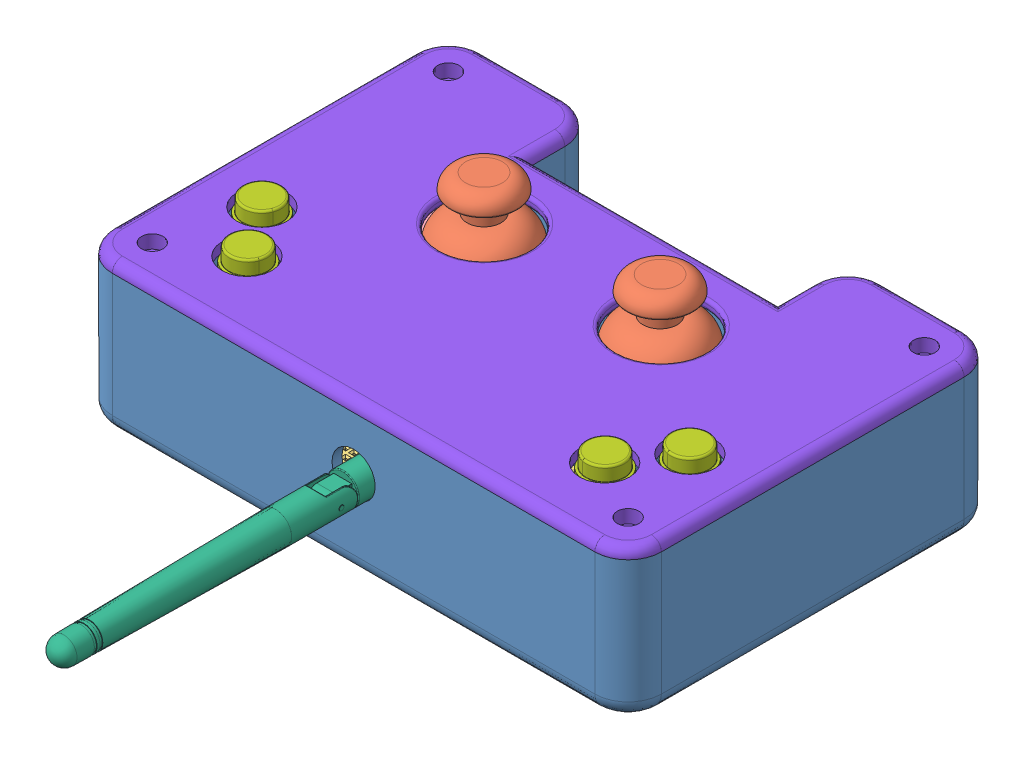
SolidWorks assembly JoystickAssembly, configuration Default. Lengths in mm.
Overall size (165 58.2 202.37).
14 component instances, 9 part files, 19 mates.
Components (placement in the parent):
- Joystick-1: Joystick [Default] at (54.0415 59.8294 130.8228) size (165 42 111)
- joy_stick_2a.step-1: joy_stick_2a.step [Default] at (94.3915 85.8294 137.6174) x (0 0 -1) z (1 0 0) size (39.77 33.6 27.6)
- joy_stick_2a.step-2: joy_stick_2a.step [Default] at (41.3913 85.8294 137.5289) x (0 0 -1) z (1 0 0) size (39.77 33.6 27.6)
- HalfBreadboard.step-1: HalfBreadboard.step [Default] at (54.0619 68.0794 113.7306) x (0 0 -1) z (1 0 0) size (56.08 9.51 83.01)
- 9V-2-1: 9V-2 [Default] at (0.3463 75.3294 87.429) x (0 1 0) z (1 0 0) size (25 49.55 16)
- NRFL24L01_Power_Board_asm-1: NRFL24L01_Power_Board_asm [Default] at (53.8164 64.2894 122.1319) size (18.6 11.5 26)
- NRF24L01L+Antenna-2: NRF24L01L+Antenna [Default] at (54.5514 76.8294 126.2969) x (0 0 1) z (-1 0 0) size (151.4 20.74 15.5)
- Button microswitch_P-B1729+B17172_blue.stp-1: Button microswitch_P-B1729+B17172_blue.stp [Default] at (118.326 95.9294 149.578) x (-0.642788 0 0.766044) z (0 1 0) size (13 13 15.4)
- Perf.stp-1: Perf.stp [Default] at (117.4296 95.9294 172.2077) x (0.642788 0 -0.766044) z (0 -1 0) size (70 50 1.55) (hidden)
- Perf.stp-2: Perf.stp [Default] at (2.032 95.9294 165.3557) x (-0.642788 0 -0.766044) z (0 -1 0) size (70 50 1.55) (hidden)
- Button microswitch_P-B1729+B17172_blue.stp-3: Button microswitch_P-B1729+B17172_blue.stp [Default] at (107.6768 95.9294 164.3561) x (-0.642788 0 0.766044) z (0 1 0) size (13 13 15.4)
- Joystick_Lid-1: Joystick_Lid [Default] at (54.0415 101.8294 130.8228) size (165 6.9 111)
- Button microswitch_P-B1729+B17172_blue.stp-4: Button microswitch_P-B1729+B17172_blue.stp [Default] at (0.4062 95.9294 164.3561) x (0.642788 0 0.766044) z (0 1 0) size (13 13 15.4)
- Button microswitch_P-B1729+B17172_blue.stp-5: Button microswitch_P-B1729+B17172_blue.stp [Default] at (-10.243 95.9294 149.578) x (0.642788 0 0.766044) z (0 1 0) size (13 13 15.4)
Mates (geometry in assembly coordinates):
- Coincident2: coincident anti-aligned: plane of Joystick-1 through (71.3417 85.8294 132.5789) normal (0 1 0); plane of joy_stick_2a.step-1 through (81.2915 85.8294 120.4674) normal (0 -1 0)
- Concentric4: concentric anti-aligned: circle of joy_stick_2a.step-1; circle of Joystick-1
- Concentric8: concentric anti-aligned: circle of Joystick-1; circle of joy_stick_2a.step-2
- Coincident4: coincident anti-aligned: plane of Joystick-1 through (38.5413 85.8294 132.5789) normal (0 1 0); plane of joy_stick_2a.step-2 through (28.2913 85.8294 120.3789) normal (0 -1 0)
- Coincident5: coincident anti-aligned: plane of Joystick-1 through (6.5415 62.8294 85.3228) normal (0 1 0); plane of HalfBreadboard.step-1 through (12.1519 62.8294 155.6406) normal (0 -1 0)
- Coincident6: coincident anti-aligned: plane of NRFL24L01_Power_Board_asm-1 through (48.7364 74.3294 132.1319) normal (0 1 0); plane of NRF24L01L+Antenna-2 through (54.5514 74.3294 126.2969) normal (0 -1 0)
- Coincident7: coincident anti-aligned: plane of NRFL24L01_Power_Board_asm-1 through (56.3564 65.8294 127.8019) normal (0 0 1); plane of NRF24L01L+Antenna-2 through (58.6264 68.3294 127.8019) normal (0 0 -1)
- Coincident8: coincident anti-aligned: plane of NRFL24L01_Power_Board_asm-1 through (58.6264 76.5837 127.8019) normal (-1 0 0); plane of NRF24L01L+Antenna-2 through (58.6264 68.3294 127.8019) normal (1 0 0)
- Coincident9: coincident anti-aligned: plane of Joystick-1 through (6.5415 62.8294 85.3228) normal (0 1 0); plane of NRFL24L01_Power_Board_asm-1 through (45.8864 62.8294 113.3819) normal (0 -1 0)
- Coincident10: coincident anti-aligned: plane of Joystick-1 through (122.8185 94.4294 143.1749) normal (0 1 0); plane of Perf.stp-1 through (117.4296 94.4294 172.2077) normal (0 -1 0)
- Coincident11: coincident anti-aligned: plane of Joystick-1 through (-14.7356 94.4294 143.1749) normal (0 1 0); plane of Perf.stp-2 through (2.032 94.4294 165.3557) normal (0 -1 0)
- Coincident12: coincident anti-aligned: plane of Button microswitch_P-B1729+B17172_red.stp-1 through (6.2688 108.9294 138.3284) normal (0 -1 0); plane of Perf.stp-2 through (2.032 95.9294 165.3557) normal (0 1 0)
- Coincident13: coincident anti-aligned: plane of Perf.stp-2 through (2.032 95.9294 165.3557) normal (0 1 0); plane of Button microswitch_P-B1729+B17172_red.stp-3 through (-37.5596 108.9294 147.4949) normal (0 -1 0)
- Coincident14: coincident anti-aligned: plane of Button microswitch_P-B1729+B17172_blue.stp-1 through (118.326 95.9294 149.578) normal (0 -1 0); plane of Perf.stp-1 through (117.4296 95.9294 172.2077) normal (0 1 0)
- Coincident15: coincident anti-aligned: plane of Perf.stp-1 through (117.4296 95.9294 172.2077) normal (0 1 0); plane of Button microswitch_P-B1729+B17172_blue.stp-3 through (107.6768 95.9294 164.3561) normal (0 -1 0)
- Coincident16: coincident anti-aligned: plane of Joystick-1 through (6.5415 62.8294 85.3228) normal (0 1 0); plane of 9V-2-1 through (8.3463 62.8294 133.429) normal (0 -1 0)
- Concentric9: concentric aligned: circle of Joystick-1; circle of Joystick_Lid-1
- Concentric10: concentric anti-aligned: circle of Joystick-1; circle of Joystick_Lid-1
- Coincident17: coincident anti-aligned: plane of Joystick-1 through (54.0415 101.8294 130.8228) normal (0 1 0); plane of Joystick_Lid-1 through (54.0415 101.8294 130.8228) normal (0 -1 0)
